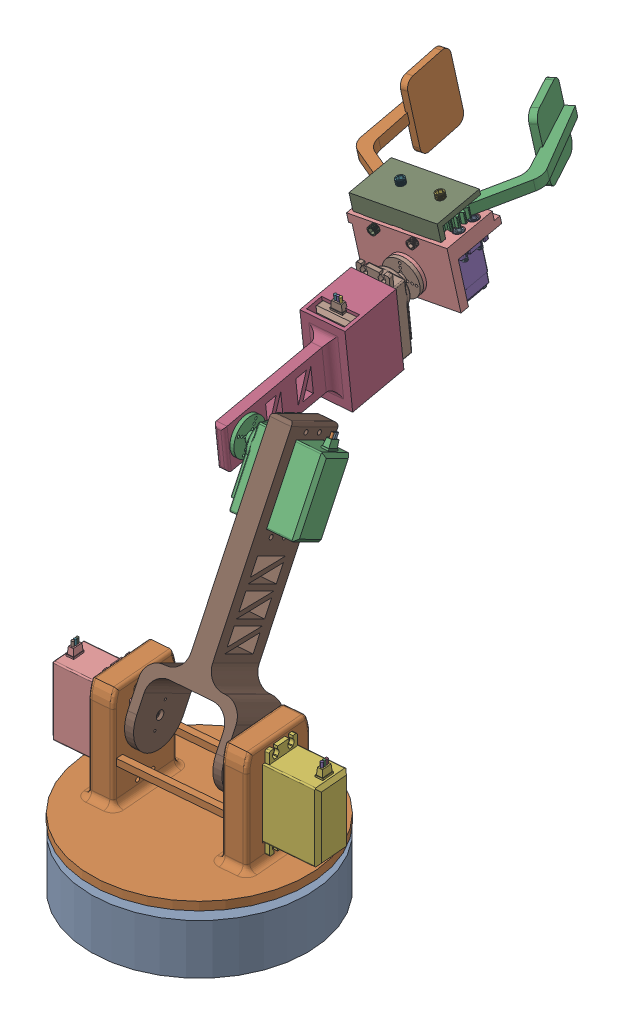
SolidWorks assembly URDF_Final_Assembly, configuration Default. Lengths in mm.
Overall size (209.45 289.73 341.39).
7 component instances, 7 part files, 13 mates.
Components (placement in the parent):
- Base_rotation-1: Base_rotation [Default] at origin size (130 30 130)
- Base_link-1: Base_link [Default] at (0 35 0) x (-0.996306 0 0.085875) z (0.085875 0 0.996306) size (148.8 66 130)
- link_1_lower-1: link_1_lower [Default] at (-0.2463 35.0743 -2.8574) x (0.996306 0 -0.085875) z (-0.08576 0.051766 -0.99497) size (54 149.38 107.69)
- link_2_upper-1: link_2_upper [Default] at (-2.4981 30.152 -28.9819) x (0.996306 0 -0.085875) z (-0.082039 0.295549 -0.951799) size (25 59.63 127.09)
- Gripper_static-1: Gripper_static [Default] at (-58.2161 228.9471 -179.9484) x (0.988774 0.131916 -0.070174) z (0.085326 -0.112957 0.989929) size (57 53.5 36.8)
- gripper ULC 2.0 left-1: gripper ULC 2.0 left [Default] at (-58.5619 237.4274 -182.055) x (0.851003 0.168108 -0.497527) z (-0.122661 0.984804 0.122944) size (41.17 97.3 40)
- gripper ULC 2.0 Right-1: gripper ULC 2.0 Right [Default] at (-37.0136 246.0089 -182.9331) x (-0.969193 -0.145524 0.198714) z (0.122661 -0.984804 -0.122944) size (41.63 92.71 40)
Mates (geometry in assembly coordinates):
- Coincident2: coincident: unknown of Base_rotation-1
- Concentric1: concentric aligned: cylinder of Base_rotation-1 through (0 30 0) axis (0 -1 0) radius 65; cylinder of Base_link-1 through (0 40 0) axis (0 -1 0) radius 65
- Distance1: distance = 5 mm anti-aligned: plane of Base_link-1 through (0 35 0) normal (0 -1 0); plane of Base_rotation-1 through (0 30 0) normal (0 1 0)
- Concentric2: concentric anti-aligned: cylinder of Base_link-1 through (-29.1136 80.75 2.2585) axis (-0.996306 0 0.085875) radius 3; cylinder of link_1_lower-1 through (-23.9328 80.75 1.8119) axis (0.996306 0 -0.085875) radius 2.5
- Coincident4: coincident anti-aligned: plane of Base_link-1; plane of link_1_lower-1 through (-29.2702 94.2919 -25.1766) normal (-0.996306 0 0.085875)
- Concentric4: concentric anti-aligned: cylinder of link_1_lower-1 through (-28.338 192.0863 -58.6123) axis (0.996306 0 -0.085875) radius 3; cylinder of link_2_upper-1 through (-21.064 192.0863 -59.2393) axis (-0.996306 0 0.085875) radius 1.3
- Coincident6: coincident anti-aligned: plane of link_1_lower-1 through (-30.5299 192.0863 -58.4234) normal (-0.996306 0 0.085875); plane of link_2_upper-1 through (-35.5147 186.1048 -116.2561) normal (0.996306 0 -0.085875)
- Coincident7: coincident anti-aligned: plane of link_2_upper-1 through (-43.0884 214.7411 -166.279) normal (-0.085326 0.112957 -0.989929); plane of Gripper_static-1 through (-43.0884 214.7411 -166.279) normal (0.085326 -0.112957 0.989929)
- Concentric5: concentric anti-aligned: cylinder of link_2_upper-1 through (-43.0884 214.7411 -166.279) axis (0.085326 -0.112957 0.989929) radius 10.5; cylinder of Gripper_static-1 through (-43.0884 214.7411 -166.279) axis (-0.085326 0.112957 -0.989929) radius 10.5
- Coincident8: coincident anti-aligned: plane of Gripper_static-1 through (-58.9299 240.3818 -181.6862) normal (0.122661 -0.984804 -0.122944); plane of gripper ULC 2.0 left-1 through (-58.9299 240.3818 -181.6862) normal (-0.122661 0.984804 0.122944)
- Concentric6: concentric anti-aligned: cylinder of Gripper_static-1 through (-58.5373 237.2304 -182.0796) axis (-0.122661 0.984804 0.122944) radius 4.4; cylinder of gripper ULC 2.0 left-1 through (-59.2978 243.3362 -181.3174) axis (0.122661 -0.984804 -0.122944) radius 4.5
- Coincident9: coincident anti-aligned: plane of Gripper_static-1 through (-69.6488 235.6479 -181.3024) normal (-0.122661 0.984804 0.122944); plane of gripper ULC 2.0 Right-1 through (-36.2777 240.1001 -183.6708) normal (0.122661 -0.984804 -0.122944)
- Concentric7: concentric aligned: cylinder of Gripper_static-1 through (-35.1737 231.2368 -184.7773) axis (-0.122661 0.984804 0.122944) radius 1.6; cylinder of gripper ULC 2.0 Right-1 through (-33.2432 215.7372 -186.7123) axis (-0.122661 0.984804 0.122944) radius 1.65
